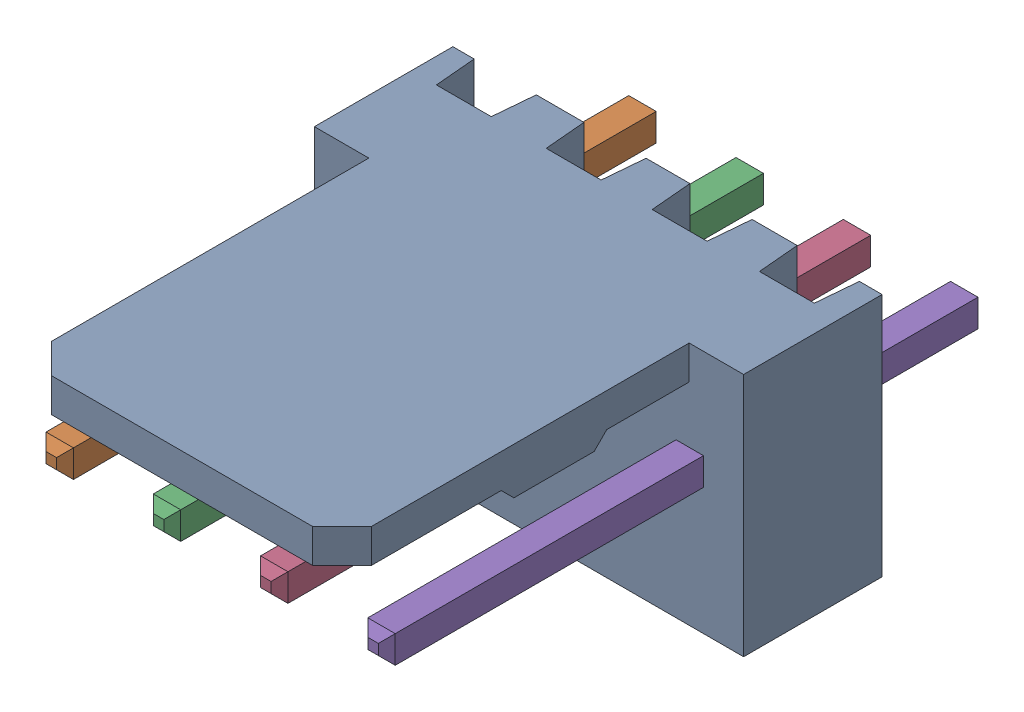
SolidWorks assembly Molex PCB 4 pin v3, configuration Predeterminado. Lengths in mm.
Overall size (10.16 5.79 14.92).
5 component instances, 2 part files, 0 mates.
Components (placement in the parent):
- BASE9710016-1: BASE9710016 [Predeterminado] at (2.54 2.895 -8.22) size (10.16 5.79 11.5)
- PINO9710016-1: PINO9710016 [Predeterminado] at (1.27 3.325 -0.72) size (0.65 0.65 14.2)
- PINO9710016-2: PINO9710016 [Predeterminado] at (3.81 3.325 -0.72) size (0.65 0.65 14.2)
- PINO9710016-3: PINO9710016 [Predeterminado] at (6.35 3.325 -0.72) size (0.65 0.65 14.2)
- PINO9710016-4: PINO9710016 [Predeterminado] at (8.89 3.325 -0.72) size (0.65 0.65 14.2)
